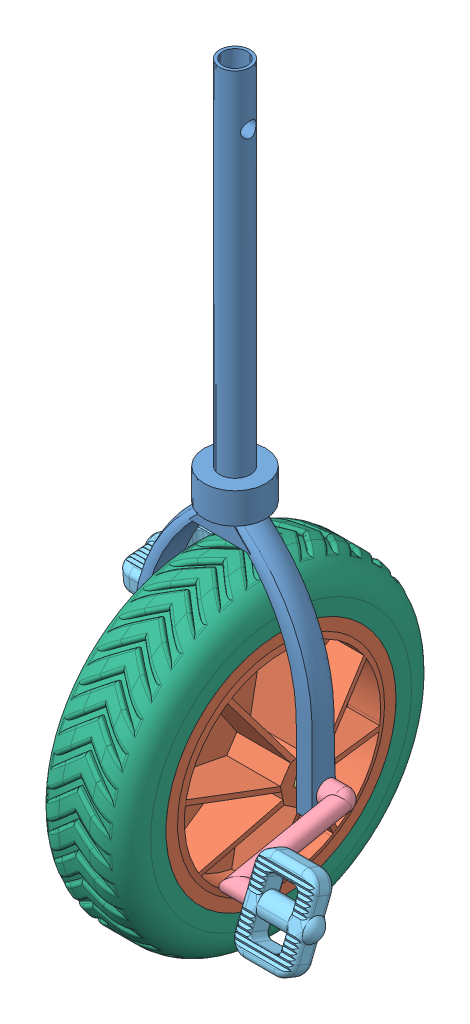
SolidWorks assembly voorvork+wiel+band, configuration Default. Lengths in mm.
Overall size (248 508.91 250.19).
8 component instances, 6 part files, 15 mates.
Components (placement in the parent):
- voorvork-1: voorvork [Default] at (100.9229 178.2623 269.7183) size (130.11 396.12 40)
- wiel-1: wiel [Default] at (100.9229 44.4443 269.7183) x (0 0.200278 -0.979739) z (1 0 0) size (179.66 179.66 90.02)
- vooras-1: vooras [Default] at (140.9229 44.4443 269.7183) x (0 -0.74834 -0.663315) z (-1 0 0) size (13.86 12 140)
- trapper1-3: trapper1 [Default] at (160.9229 44.4443 269.7183) x (0 -0.200278 0.979739) z (0 0.979739 0.200278) size (83 60 14)
- trapper1-4: trapper1 [Default] at (40.9229 44.4443 269.7183) x (0 0.200278 -0.979739) z (0 0.979739 0.200278) size (83 60 14)
- trapper2-1: trapper2 [Default] at (20.9229 57.9534 207.1148) x (0 0.085065 -0.996375) z (1 0 0) size (55 15.8 44)
- trapper2-2: trapper2 [Default] at (180.9229 36.0058 336.0969) x (0 -0.930146 0.36719) z (-1 0 0) size (55 15.8 44)
- voorband-1: voorband [Default] at (70.9229 44.4443 269.7183) x (0 0.189897 0.981804) z (1 0 0) size (213.53 213.53 60)
Mates (geometry in assembly coordinates):
- Concentric1: concentric aligned: cylinder of voorvork-1 through (40.8562 44.4443 269.7183) axis (1 0 0) radius 6.25; circle of vooras-1
- Concentric2: concentric aligned: circle of vooras-1; circle of trapper1-4
- Coincident2: coincident aligned: circle of vooras-1; circle of trapper1-4
- Coincident3: coincident aligned: circle of vooras-1; circle of trapper1-3
- Parallel1: parallel anti-aligned: cylinder of trapper1-3 through (170.9229 27.7612 351.3305) axis (0 0.200278 -0.979739) radius 6; cylinder of trapper1-4 through (30.9229 61.1275 188.106) axis (0 -0.200278 0.979739) radius 6
- Tangent5: tangent aligned: plane of vooras-1 through (60.9229 49.629 274.3138) normal (0 0.979739 0.200278); cylinder of trapper1-3 through (220.9229 30.4249 338.3) axis (-1 0 0) radius 6
- Coincident5: coincident aligned: plane of voorvork-1 through (100.9229 178.2623 269.7183) normal (1 0 0); plane of vooras-1 through (100.9229 44.4443 269.7183) normal (1 0 0)
- Coincident6: coincident aligned: circle of trapper1-3; circle of trapper2-2
- Coincident7: coincident aligned: circle of trapper1-4; circle of trapper2-1
- Coincident15: coincident anti-aligned: plane of wiel-1 through (100.9229 45.8319 262.9304) normal (0 -0.663315 0.74834); plane of vooras-1 through (60.9229 51.0165 267.526) normal (0 0.663315 -0.74834)
- Coincident17: coincident aligned: line of wiel-1 through (55.9229 39.2597 265.1227) axis (1 0 0); line of vooras-1 through (60.9229 39.2597 265.1227) axis (1 0 0)
- Coincident18: coincident aligned: plane of voorvork-1 through (100.9229 178.2623 269.7183) normal (1 0 0); plane of wiel-1 through (100.9229 44.4443 269.7183) normal (1 0 0)
- Concentric4: concentric aligned: cylinder of wiel-1 through (80.9229 44.4443 269.7183) axis (1 0 0) radius 90; cylinder of voorband-1 through (80.9229 44.4443 269.7183) axis (1 0 0) radius 90
- Coincident19: coincident anti-aligned: plane of wiel-1 through (80.9229 44.4443 269.7183) normal (-1 0 0); plane of voorband-1 through (80.9229 44.4443 269.7183) normal (1 0 0)
- Coincident20: coincident anti-aligned: plane of wiel-1 through (70.9229 44.4443 269.7183) normal (0 0.981804 -0.189897); plane of voorband-1
